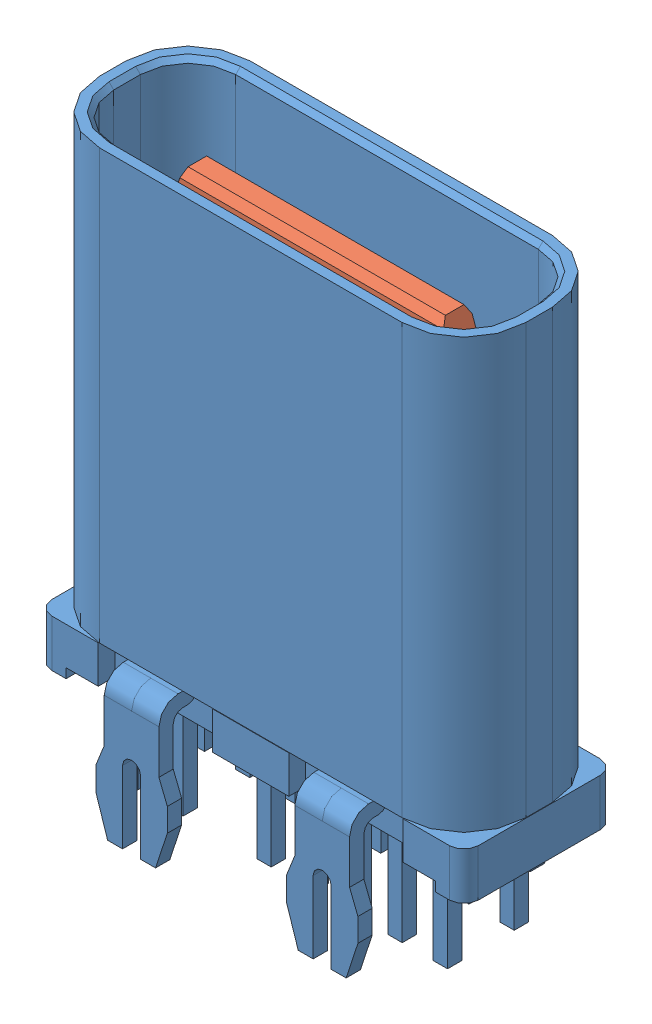
SolidWorks assembly Type-c-14p_vertical_H-10mm, configuration Default. Lengths in mm.
Overall size (8.95 12 4.16).
2 component instances, 2 part files, 6 mates.
Components (placement in the parent):
- TYPE-C-14-vertical_H-10mm-1: TYPE-C-14-vertical_H-10mm [Default] at (5.4229 12 3.1541) x (1 0 0) z (0 0 -1) size (8.95 12 4.16)
- TYPE-C-塑料内芯-1: TYPE-C-塑料内芯 [默认] at (9.8979 12 1.5741) x (-1 0 0) z (0 0 1) size (5.96 8.21 0.61)
Mates (geometry in assembly coordinates):
- 重合1: coincident anti-aligned: plane of TYPE-C-14-vertical_H-10mm-1 through (5.4229 12 3.1541) normal (1 0 0); plane of TYPE-C-塑料内芯-1 through (5.4229 12 1.5741) normal (-1 0 0)
- 重合2: coincident aligned: plane of TYPE-C-14-vertical_H-10mm-1 through (5.4229 12 3.1541) normal (0 0 1); plane of TYPE-C-塑料内芯-1 through (9.8979 12 3.1541) normal (0 0 1)
- 重合3: coincident anti-aligned: plane of TYPE-C-14-vertical_H-10mm-1 through (5.4229 2.99 3.1541) normal (0 1 0); plane of TYPE-C-塑料内芯-1 through (9.8979 2.99 1.5741) normal (0 -1 0)
- 重合4: coincident anti-aligned: plane of TYPE-C-14-vertical_H-10mm-1 through (5.4229 0 3.1541) normal (0 -1 0); plane of assembly through (0 0 0) normal (0 1 0)
- 重合6: coincident anti-aligned: plane of TYPE-C-14-vertical_H-10mm-1 through (5.4229 12 3.1541) normal (1 0 0); plane of TYPE-C-塑料内芯-1 through (5.4229 12 1.5741) normal (-1 0 0)
- 重合7: coincident anti-aligned: plane of TYPE-C-14-vertical_H-10mm-1 through (5.4229 12 3.1541) normal (0 0 -1); plane of TYPE-C-塑料内芯-1 through (9.8979 12 3.1541) normal (0 0 1)
